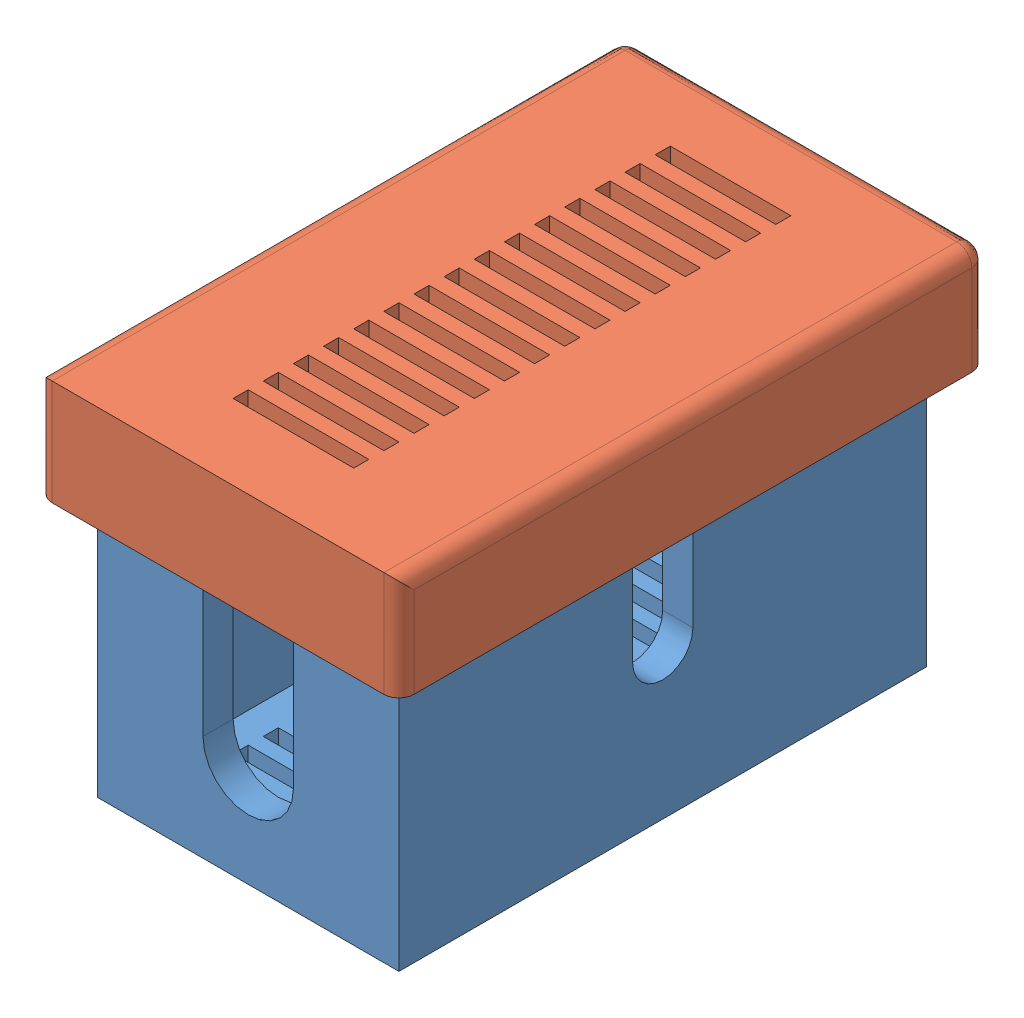
SolidWorks assembly Baugruppe_PDU-Hausung, configuration Standard. Lengths in mm.
Overall size (24 24.42 39).
2 component instances, 2 part files, 2 mates.
Components (placement in the parent):
- PDU_Gehäuse-1: PDU_Gehäuse [Standard] at (-24.2483 -1.762 -17.5) size (20 20 35)
- PDU_Deckel-1: PDU_Deckel [Standard] at (-24.2483 15.6551 -17.5) size (24 7 39)
Mates (geometry in assembly coordinates):
- Senkrecht1: perpendicular: plane of PDU_Gehäuse-1 through (-24.2483 18.238 17.5) normal (0 1 0); plane of PDU_Deckel-1 through (-26.2483 15.6551 17.5) normal (-1 0 0)
- Deckungsgleich2: coincident aligned: line of PDU_Gehäuse-1 through (-4.2483 -1.762 -17.5) axis (0 1 0); line of PDU_Deckel-1 through (-4.2483 16.6551 -17.5) axis (0 1 0)
